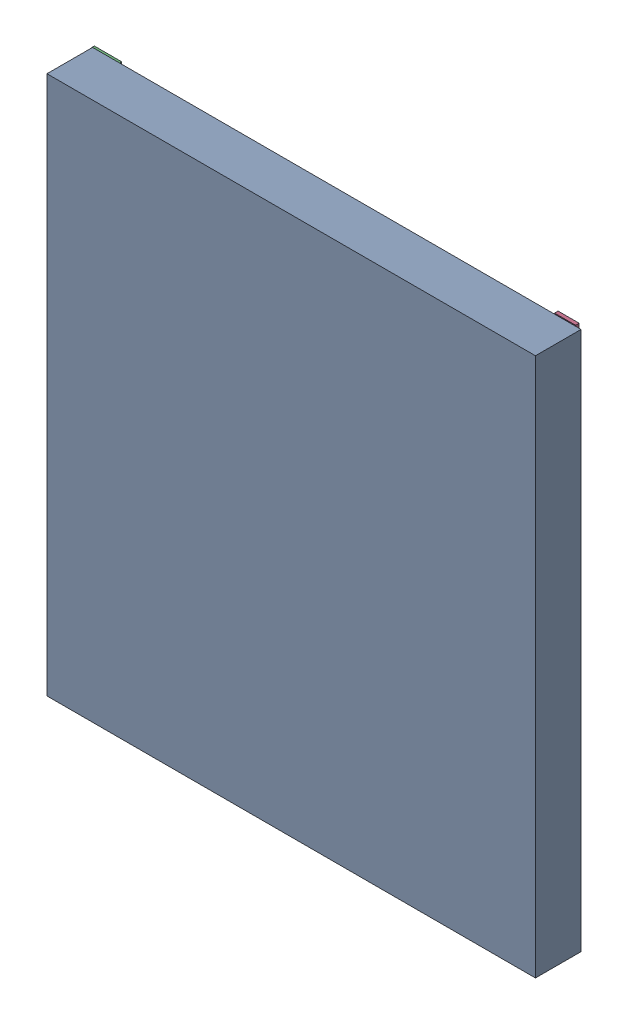
SolidWorks assembly J2_2.step, configuration Default. Lengths in mm.
Overall size (13.87 15.46 1.39).
3 component instances, 2 part files, 0 mates.
Components (placement in the parent):
- 12876872368.step-1: 12876872368.step [Default] at (88.3 99.752 0) x (-1 0 0) z (0 0 1) size (13.87 15.46 1.39)
  - Body_8.step-4: Body_8.step [Default] at (0 0 0.1) size (13.82 15.25 1.29)
  - Pins_4.step-4: Pins_4.step [Default] at origin size (13.72 15.46 0.1)
